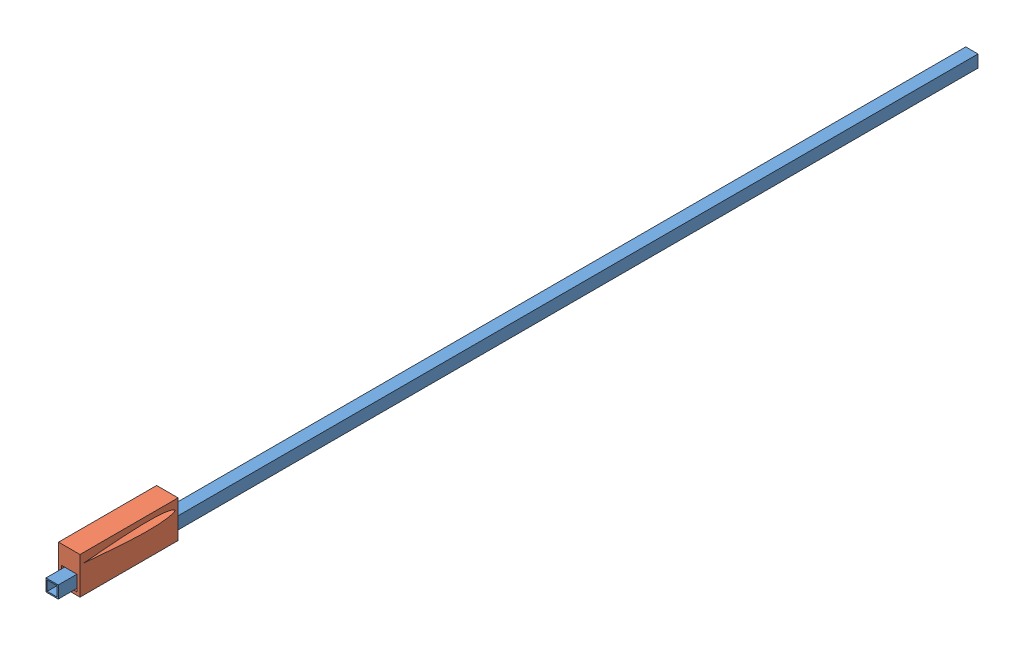
SolidWorks assembly tail assy, configuration Default. Lengths in mm.
Overall size (38.29 62.81 1500).
4 component instances, 3 part files, 0 mates.
Components (placement in the parent):
- tail spar-1: tail spar [Default] at (-45.3141 12.4761 -734.5645) size (20 20 1500)
- TAIL2023-1: TAIL2023 [Default] at (-17.025 -3.6526 579.9895) size (35.5 62.81 203.79)
  - bracket^TAIL2023-1: bracket^TAIL2023 [Default] at origin size (35.5 62.81 160) (virtual)
  - airfoil 0009-1: airfoil 0009 [Default] at (-28.498 54.9732 -43.7891) x (0 0 1) z (-1 0 0) size (1 0.09 0)
